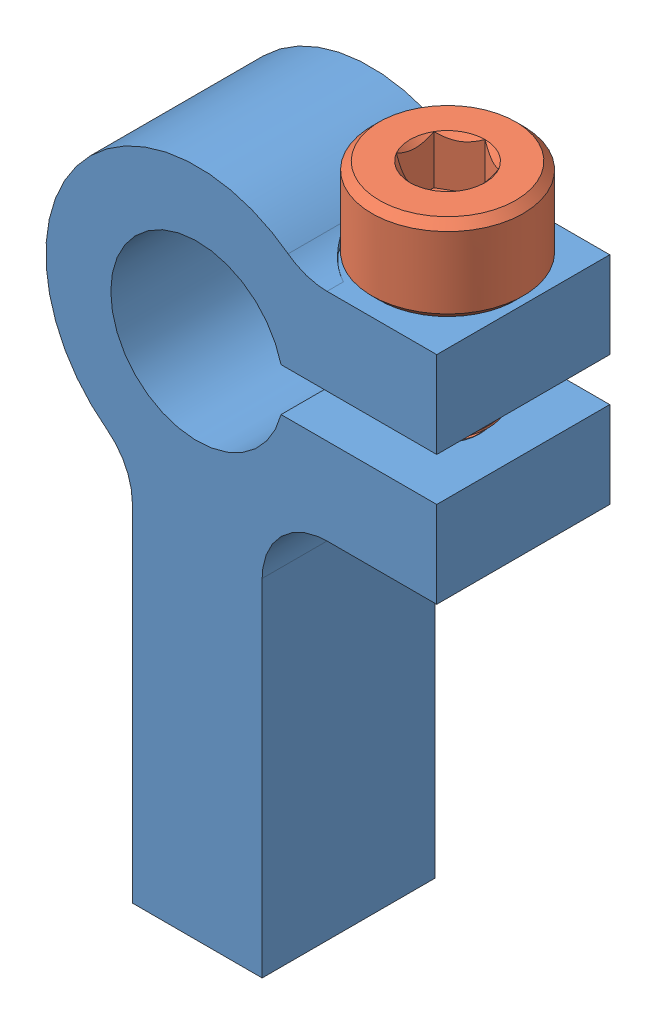
SolidWorks assembly 1-Side, 1-Post Clamping Mount (8mm Bore) 1403-0024-0008, configuration Default. Lengths in mm.
Overall size (18.07 33.01 8).
2 component instances, 2 part files, 0 mates.
Components (placement in the parent):
- 1403-0024-0008 without hardware.step-1: 1403-0024-0008 without hardware.step [Default] at (-13.0541 1.4088 -5.2736) size (18.07 31 8)
- 2800-0004-0010.step-1: 2800-0004-0010.step [Default] at (-5.4812 -3.5912 -1.2736) size (7 14.01 7)
